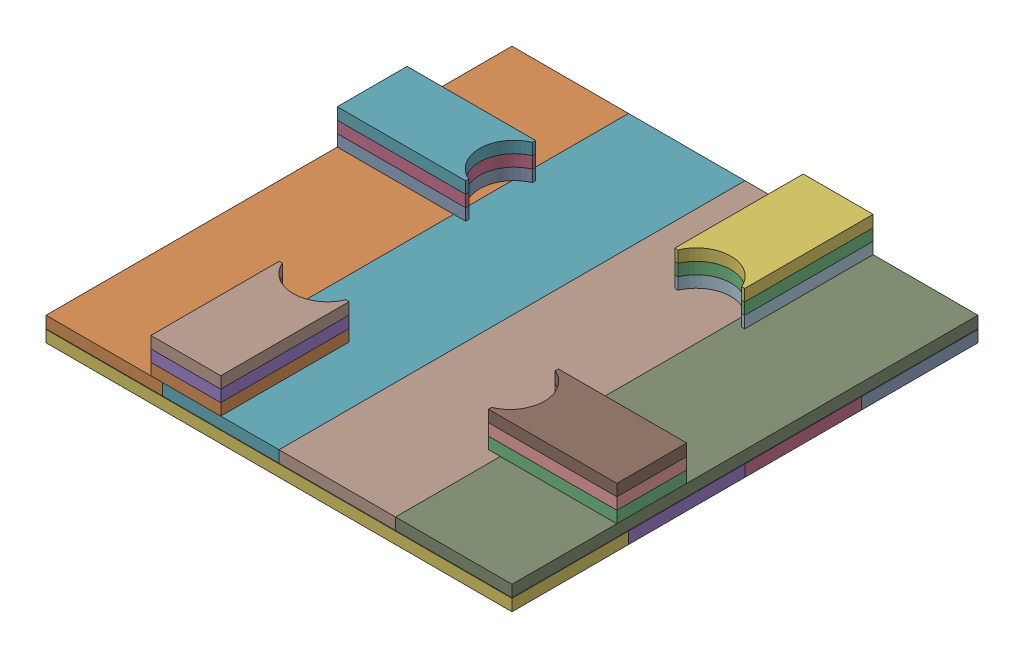
SolidWorks assembly Поддон2, configuration По умолчанию. Lengths in mm.
Overall size (800 101 800).
20 component instances, 2 part files, 6 mates.
Components (placement in the parent):
- Доска250-1: Доска250 [По умолчанию] at origin size (800 20 200)
- Доска250-5: Доска250 [По умолчанию] at (-300 21 300) x (0 0 -1) z (1 0 0) size (800 20 200)
- ПАЗ-1: ПАЗ [По умолчанию] at (289.7504 41 460) size (220.5 20 120)
- Доска250-2: Доска250 [По умолчанию] at (0 0 200) size (800 20 200)
- Доска250-3: Доска250 [По умолчанию] at (0 0 400) size (800 20 200)
- Доска250-4: Доска250 [По умолчанию] at (0 0 600) size (800 20 200)
- Доска250-6: Доска250 [По умолчанию] at (-100 21 300) x (0 0 -1) z (1 0 0) size (800 20 200)
- Доска250-7: Доска250 [По умолчанию] at (100 21 300) x (0 0 -1) z (1 0 0) size (800 20 200)
- Доска250-8: Доска250 [По умолчанию] at (300 21 300) x (0 0 -1) z (1 0 0) size (800 20 200)
- ПАЗ-2: ПАЗ [По умолчанию] at (289.7504 61 460) size (220.5 20 120)
- ПАЗ-3: ПАЗ [По умолчанию] at (289.7504 81 460) size (220.5 20 120)
- ПАЗ-4: ПАЗ [По умолчанию] at (160 41 10.2496) x (0 0 -1) z (1 0 0) size (220.5 20 120)
- ПАЗ-5: ПАЗ [По умолчанию] at (-289.7504 41 140) x (-1 0 0) z (0 0 -1) size (220.5 20 120)
- ПАЗ-6: ПАЗ [По умолчанию] at (-160 41 589.7504) x (0 0 1) z (-1 0 0) size (220.5 20 120)
- ПАЗ-7: ПАЗ [По умолчанию] at (160 61 10.2496) x (0 0 -1) z (1 0 0) size (220.5 20 120)
- ПАЗ-8: ПАЗ [По умолчанию] at (-289.7504 61 140) x (-1 0 0) z (0 0 -1) size (220.5 20 120)
- ПАЗ-9: ПАЗ [По умолчанию] at (-160 61 589.7504) x (0 0 1) z (-1 0 0) size (220.5 20 120)
- ПАЗ-10: ПАЗ [По умолчанию] at (160 81 10.2496) x (0 0 -1) z (1 0 0) size (220.5 20 120)
- ПАЗ-11: ПАЗ [По умолчанию] at (-289.7504 81 140) x (-1 0 0) z (0 0 -1) size (220.5 20 120)
- ПАЗ-12: ПАЗ [По умолчанию] at (-160 81 589.7504) x (0 0 1) z (-1 0 0) size (220.5 20 120)
Mates (geometry in assembly coordinates):
- Совпадение2: coincident aligned: plane of Доска250-1 through (-400 20 100) normal (-1 0 0); plane of Доска250-5 through (-400 41 700) normal (-1 0 0)
- Расстояние1: distance = 1 mm anti-aligned: plane of Доска250-5 through (-300 21 300) normal (0 -1 0); plane of Доска250-1 through (0 20 0) normal (0 1 0)
- Совпадение4: coincident aligned: plane of Доска250-1 through (-400 20 -100) normal (0 0 -1); plane of Доска250-5 through (-400 41 -100) normal (0 0 -1)
- Расстояние2: distance = 180 mm aligned: plane of ПАЗ-1 through (179.5008 61 520) normal (0 0 1); plane of Доска250-8 through (400 41 700) normal (0 0 1)
- Совпадение6: coincident anti-aligned: plane of Доска250-8 through (300 41 300) normal (0 1 0); plane of ПАЗ-1 through (156.413 41 460) normal (0 -1 0)
- Расстояние3: distance = 0 mm aligned: plane of ПАЗ-1 through (400 61 400) normal (1 0 0); plane of Доска250-8 through (400 41 700) normal (1 0 0)
